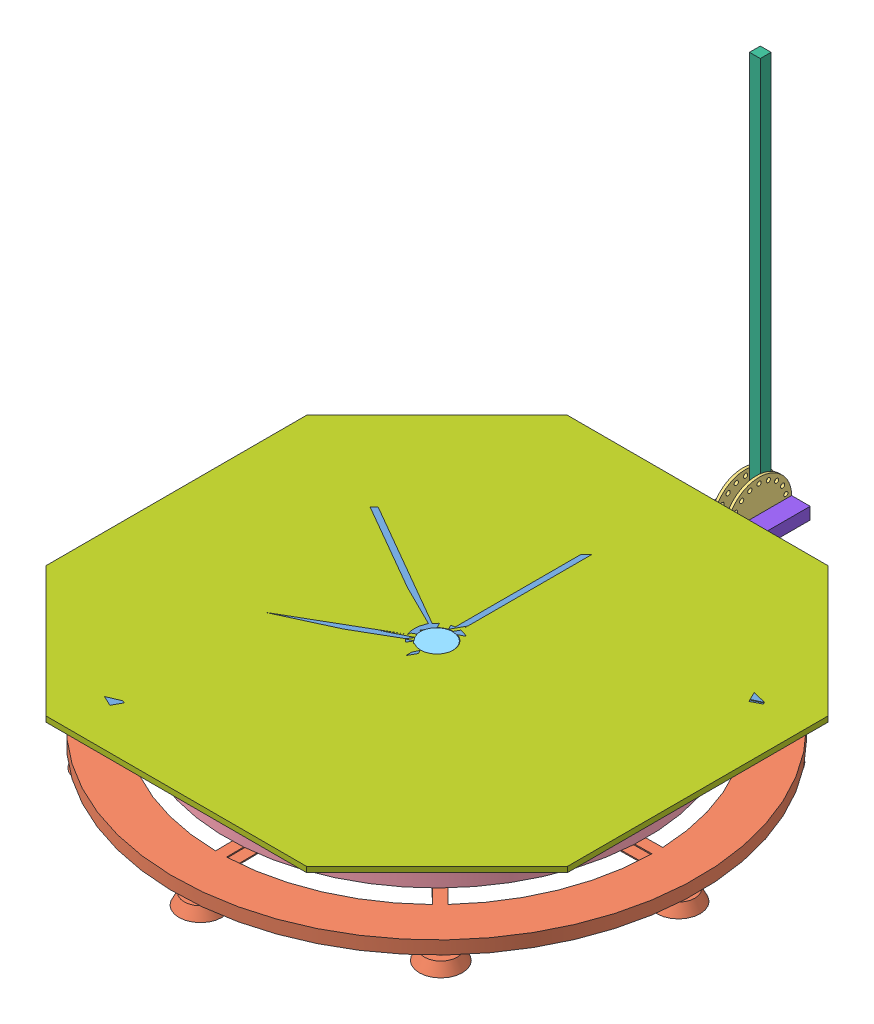
SolidWorks assembly Assem1, configuration Default. Lengths in mm.
Overall size (1240.44 1082.43 1415.61).
8 component instances, 8 part files, 12 mates.
Components (placement in the parent):
- chassy top-2: chassy top [Default] at (561.375 -76.0489 -976.7433) x (1 0 0) z (0 -1 0) size (1143 1143 63.5)
- chasse - Copy-2: chasse - Copy [Default] at (599.475 -248.993 -976.7433) x (0.013292 0 0.999912) z (0.999912 0 -0.013292) size (1224.28 78.74 1224.28)
- clip-2: clip [Default] at (597.3049 -134.2826 -1695.9335) size (38.1 76.2 152.4)
- mid holder rotating-2: mid holder rotating [Default] at (599.475 -201.2114 -976.7433) x (0.03805 0 -0.999276) z (0.999276 0 0.03805) size (1027.22 76.2 982.56)
- rod-2: rod [Default] at (599.475 -251.533 -976.7433) x (0.831036 0 0.556218) z (-0.556218 0 0.831036) size (76.2 203.2 76.2)
- selfy stick holder-2: selfy stick holder [Default] at (616.4311 -131.7621 -1717.6518) x (0 0 -1) z (1 0 0) size (25.4 914.4 25.4)
- plate-4: plate [Default] at (599.6774 -61.033 -978.0933) size (1219.2 12.7 1219.2)
- U clip-5: U clip [Default] at (614.3114 -160.9526 -1724.961) x (-1 0 0) z (0 0 -1) size (125.22 27.94 304.81)
Mates (geometry in assembly coordinates):
- Concentric1: concentric anti-aligned: cylinder of chassy top-2 through (599.475 -61.033 -976.7433) axis (0 1 0) radius 38.1; cylinder of rod-2 through (599.475 -48.333 -976.7433) axis (0 -1 0) radius 38.1
- Concentric2: concentric aligned: cylinder of mid holder rotating-2 through (599.475 -125.0114 -976.7433) axis (0 -1 0) radius 37.2213; cylinder of rod-2 through (599.475 -48.333 -976.7433) axis (0 -1 0) radius 38.1
- Concentric3: concentric anti-aligned: cylinder of chasse - Copy-2 through (599.475 -223.593 -976.7433) axis (0 1 0) radius 35.56; cylinder of rod-2 through (599.475 -48.333 -976.7433) axis (0 -1 0) radius 38.1
- Coincident2: coincident aligned: plane of chasse - Copy-2 through (599.475 -251.533 -976.7433) normal (0 -1 0); plane of rod-2 through (599.475 -251.533 -976.7433) normal (0 -1 0)
- Coincident11: coincident aligned: plane of chassy top-2 through (27.975 -48.333 -976.7433) normal (0 1 0); plane of rod-2 through (599.475 -48.333 -976.7433) normal (0 1 0)
- Coincident12: coincident aligned: plane of chassy top-2 through (27.975 -48.333 -976.7433) normal (0 1 0); plane of plate-4 through (599.6774 -48.333 -978.0933) normal (0 1 0)
- Coincident20: coincident anti-aligned: plane of mid holder rotating-2 through (576.7576 -135.5526 -1361.4263) normal (0 -1 0); plane of U clip-5 through (614.3114 -135.5526 -1724.961) normal (0 1 0)
- Coincident22: coincident anti-aligned: plane of clip-2 through (635.4049 -134.2826 -1619.7335) normal (0 -1 0); plane of U clip-5 through (614.3114 -134.2826 -1724.961) normal (0 1 0)
- Coincident23: coincident anti-aligned: plane of clip-2 through (635.4049 -134.2826 -1695.9335) normal (1 0 0); plane of U clip-5 through (635.4049 -134.2826 -1618.5019) normal (-1 0 0)
- Coincident24: coincident aligned: plane of clip-2 through (597.3049 -134.2826 -1771.8644) normal (0 0 -1); plane of U clip-5 through (553.7439 -135.5526 -1771.8644) normal (0 0 -1)
- Concentric4: concentric: circle of clip-2; circle of selfy stick holder-2
- Coincident27: coincident anti-aligned: plane of clip-2 through (603.7311 -58.0826 -1615.6949) normal (1 0 0); plane of selfy stick holder-2 through (603.7311 782.6379 -1730.3518) normal (-1 0 0)
